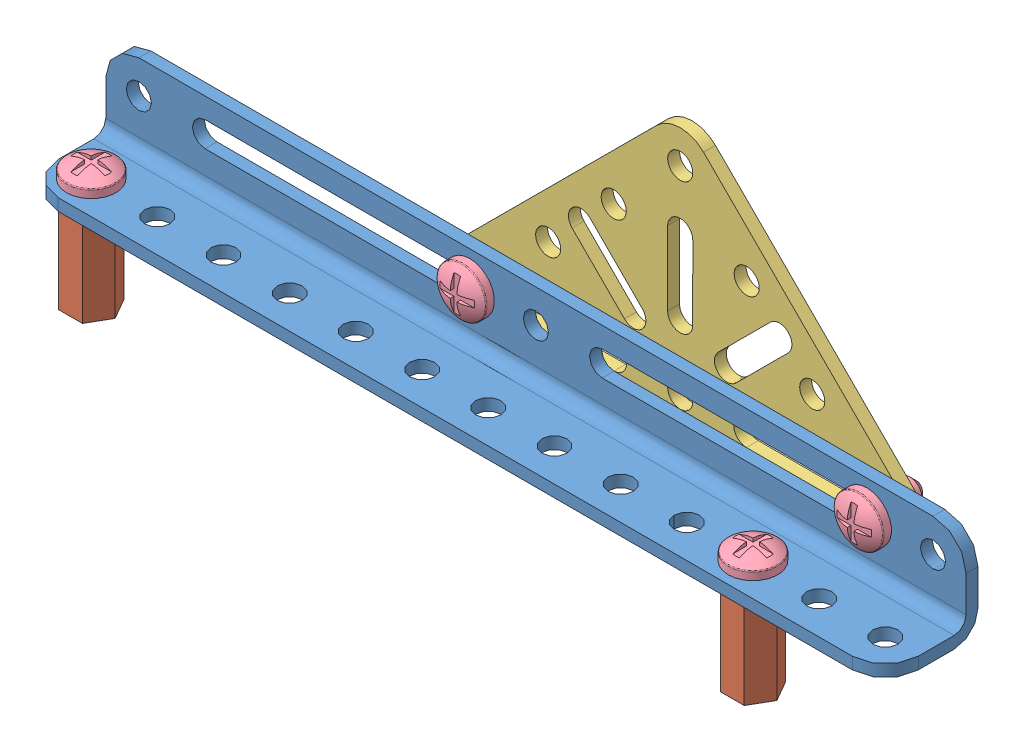
SolidWorks assembly FRONT-SUPPORT, configuration Default. Lengths in mm.
Overall size (165.1 74.5 25.02).
8 component instances, 4 part files, 17 mates.
Components (placement in the parent):
- ANGLE-13 HOLE-1: ANGLE-13 HOLE [Default] at (56.2617 82.4432 134.934) size (165.1 17.78 17.78)
- HEX-STANDOFF-1: HEX-STANDOFF [Default] at (-19.9383 63.7732 128.584) x (0.5 0 0.866025) z (-0.866025 0 0.5) size (9.18 18.67 7.95)
- HEX-STANDOFF-2: HEX-STANDOFF [Default] at (107.0617 63.7732 128.584) x (0.5 0 0.866025) z (-0.866025 0 0.5) size (9.18 18.67 7.95)
- TRIANGLE-1: TRIANGLE [Default] at (81.6617 93.8732 114.868) size (88.9 50.75 2.29)
- SCREW-1: SCREW [Default] at (107.0617 75.2042 128.584) size (9.47 12.65 9.47)
- SCREW-2: SCREW [Default] at (119.7617 93.8732 109.915) x (1 0 0) z (0 -1 0) size (9.47 12.65 9.47)
- SCREW-3: SCREW [Default] at (-19.9383 75.2042 128.584) size (9.47 12.65 9.47)
- SCREW-6: SCREW [Default] at (43.5617 93.8732 109.915) x (1 0 0) z (0 -1 0) size (9.47 12.65 9.47)
Mates (geometry in assembly coordinates):
- Concentric1: concentric aligned: cylinder of ANGLE-13 HOLE-1 through (-19.9383 82.4432 128.584) axis (0 1 0) radius 2.413; cylinder of HEX-STANDOFF-1 through (-19.9383 82.4432 128.584) axis (0 1 0) radius 2.413
- Coincident1: coincident anti-aligned: plane of ANGLE-13 HOLE-1 through (138.8117 82.4432 134.934) normal (0 -1 0); plane of HEX-STANDOFF-1 through (-17.6433 82.4432 132.559) normal (0 1 0)
- Parallel1: parallel aligned: plane of ANGLE-13 HOLE-1 through (138.8117 87.0152 119.44) normal (0 0 1); plane of HEX-STANDOFF-1 through (-22.2333 82.4432 132.559) normal (0 0 1)
- Concentric2: concentric aligned: cylinder of ANGLE-13 HOLE-1 through (107.0617 82.4432 128.584) axis (0 1 0) radius 2.413; cylinder of HEX-STANDOFF-2 through (107.0617 82.4432 128.584) axis (0 1 0) radius 2.413
- Coincident3: coincident: line of ANGLE-13 HOLE-1 through (132.4617 82.4432 134.934) axis (-1 0 0); plane of HEX-STANDOFF-2 through (109.3567 82.4432 132.559) normal (0 1 0)
- Parallel2: parallel aligned: plane of ANGLE-13 HOLE-1 through (138.8117 87.0152 119.44) normal (0 0 1); plane of HEX-STANDOFF-2 through (104.7667 82.4432 132.559) normal (0 0 1)
- Concentric3: concentric aligned: cylinder of ANGLE-13 HOLE-1 through (119.7617 93.8732 117.154) axis (0 0 1) radius 2.413; cylinder of TRIANGLE-1 through (119.7617 93.8732 114.868) axis (0 0 1) radius 2.413
- Distance1: distance = 0 mm anti-aligned: plane of TRIANGLE-1 through (43.5617 93.8732 117.154) normal (0 0 1); plane of ANGLE-13 HOLE-1 through (138.8117 87.0152 117.154) normal (0 0 -1)
- Parallel3: parallel aligned: plane of ANGLE-13 HOLE-1 through (138.8117 82.4432 134.934) normal (0 -1 0); plane of TRIANGLE-1 through (119.7617 87.5232 117.154) normal (0 -1 0)
- Concentric41: concentric anti-aligned: cylinder of ANGLE-13 HOLE-1 through (107.0617 82.4432 128.584) axis (0 1 0) radius 2.413; cylinder of SCREW-1 through (107.0617 75.2042 128.584) axis (0 -1 0) radius 4.7371
- Coincident71: coincident anti-aligned: plane of ANGLE-13 HOLE-1 through (138.8117 84.7292 134.934) normal (0 1 0); plane of SCREW-1 through (109.4747 84.7292 128.584) normal (0 -1 0)
- Concentric51: concentric anti-aligned: cylinder of ANGLE-13 HOLE-1 through (119.7617 93.8732 117.154) axis (0 0 1) radius 2.413; cylinder of SCREW-2 through (119.7617 93.8732 109.915) axis (0 0 -1) radius 4.7371
- Coincident81: coincident anti-aligned: plane of ANGLE-13 HOLE-1 through (138.8117 87.0152 119.44) normal (0 0 1); plane of SCREW-2 through (122.1747 93.8732 119.44) normal (0 0 -1)
- Concentric61: concentric anti-aligned: cylinder of ANGLE-13 HOLE-1 through (-19.9383 82.4432 128.584) axis (0 1 0) radius 2.413; cylinder of SCREW-3 through (-19.9383 75.2042 128.584) axis (0 -1 0) radius 4.7371
- Coincident91: coincident anti-aligned: plane of ANGLE-13 HOLE-1 through (138.8117 84.7292 134.934) normal (0 1 0); plane of SCREW-3 through (-17.5253 84.7292 128.584) normal (0 -1 0)
- Concentric91: concentric: cylinder of ANGLE-13 HOLE-1 through (43.5617 93.8732 117.154) axis (0 0 1) radius 2.413; cylinder of SCREW-6 through (-13.601 103.5154 211.3435) axis (0 -1 0) radius 4.7371
- Coincident121: coincident: plane of ANGLE-13 HOLE-1 through (138.8117 87.0152 119.44) normal (0 0 1); plane of SCREW-6 through (-11.188 113.0404 211.3435) normal (0 -1 0)
